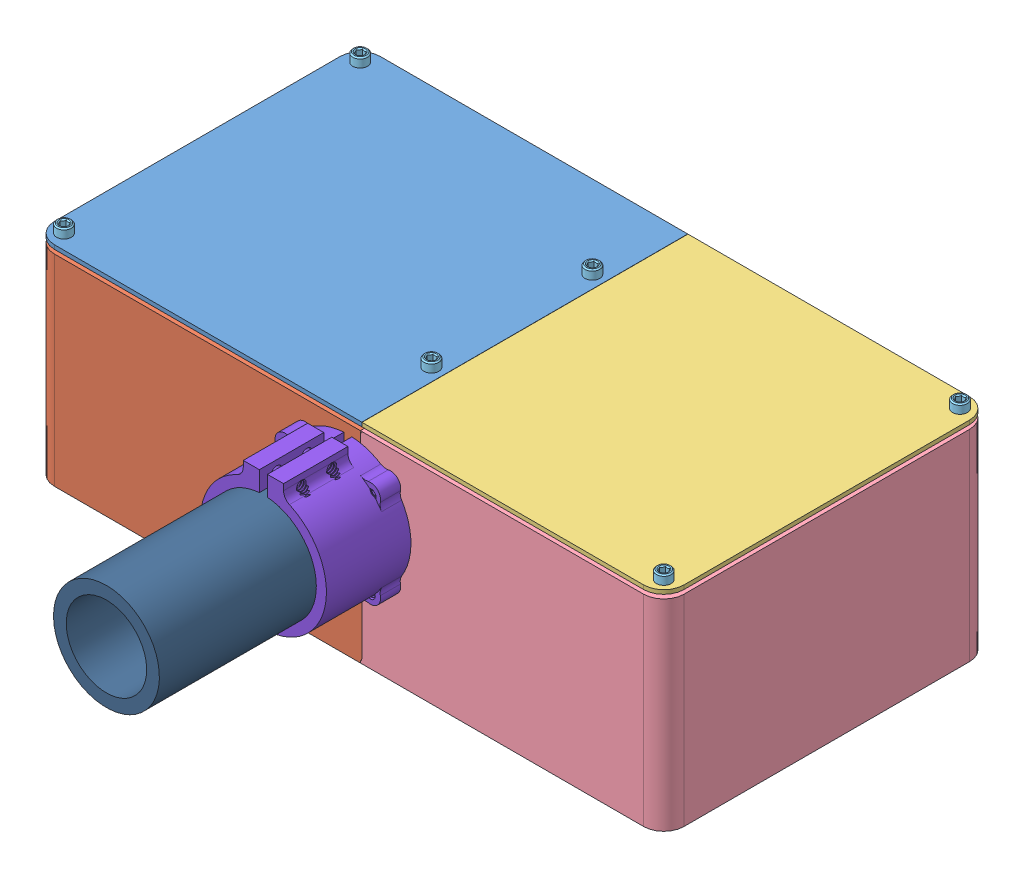
SolidWorks assembly Head Assembly, configuration Default. Lengths in mm.
Overall size (198.69 68.88 181.91).
37 component instances, 13 part files, 51 mates.
Components (placement in the parent):
- Head left back-1: Head left back [Default] at (33.2426 59.719 88.4474) size (103.38 2.54 102.87)
- Head left side-1: Head left side [Left Side] at (83.0901 -3.781 88.4474) size (103.5 63.5 102.87)
- Head right back-1: Head right back [Default] at (132.2391 59.719 88.4474) size (103.5 5.08 102.87)
- Head right side-1: Head right side [Right Side] at (82.3916 -3.781 88.4474) size (103.61 63.5 102.87)
- 4-40_SHCS-1: 4-40_SHCS [4-40 SHCS X .250] at (177.3876 55.909 135.1834) x (1 0 0) z (0 1 0) size (4.65 4.65 9.19)
- 4-40_SHCS-2: 4-40_SHCS [4-40 SHCS X .250] at (82.7091 55.909 113.8474) x (1 0 0) z (0 1 0) size (4.65 4.65 9.19)
- 4-40_SHCS-3: 4-40_SHCS [4-40 SHCS X .250] at (82.7091 55.909 63.0474) x (1 0 0) z (0 1 0) size (4.65 4.65 9.19)
- 4-40_SHCS-4: 4-40_SHCS [4-40 SHCS X .250] at (177.3876 55.909 41.7114) x (1 0 0) z (0 1 0) size (4.65 4.65 9.19)
- 4-40_SHCS-5: 4-40_SHCS [4-40 SHCS X .250] at (-11.9059 55.909 135.1834) x (0.995254 0 0.097312) z (0 1 0) size (4.65 4.65 9.19)
- 4-40_SHCS-6: 4-40_SHCS [4-40 SHCS X .250] at (-11.9059 55.909 41.7114) x (-0.428601 0 -0.903494) z (0 1 0) size (4.65 4.65 9.19)
- 4-40_SHCS-7: 4-40_SHCS [4-40 SHCS X .250] at (82.3916 38.129 43.3624) x (-0.923728 -0.383049 0) z (0 0 -1) size (4.65 4.65 9.19)
- 4-40_SHCS-8: 4-40_SHCS [4-40 SHCS X .250] at (82.3916 17.809 43.3624) x (-0.923728 -0.383049 0) z (0 0 -1) size (4.65 4.65 9.19)
- hex_nut-1: hex_nut [#4-40] at (150.3366 25.429 58.4119) x (-0.837169 0 -0.546944) z (-0.546944 0 0.837169) size (6.35 2.49 8.06)
- hex_nut-2: hex_nut [#4-40] at (116.0466 25.429 58.4119) x (-0.837169 0 -0.546944) z (-0.546944 0 0.837169) size (6.35 2.49 8.06)
- hex_nut-3: hex_nut [#4-40] at (116.0466 25.429 118.4829) x (-0.837169 0 -0.546944) z (-0.546944 0 0.837169) size (6.35 2.49 8.06)
- hex_nut-4: hex_nut [#4-40] at (150.3366 25.429 118.4829) x (-0.837169 0 -0.546944) z (-0.546944 0 0.837169) size (6.35 2.49 8.06)
- 4-40_SHCS-9: 4-40_SHCS [4-40 SHCS X .250] at (150.3366 22.889 58.4119) x (1 0 0) z (0 1 0) size (4.65 4.65 9.19)
- 4-40_SHCS-10: 4-40_SHCS [4-40 SHCS X .250] at (116.0466 22.889 58.4119) x (1 0 0) z (0 1 0) size (4.65 4.65 9.19)
- 4-40_SHCS-11: 4-40_SHCS [4-40 SHCS X .250] at (150.3366 22.889 118.4829) x (1 0 0) z (0 1 0) size (4.65 4.65 9.19)
- 4-40_SHCS-12: 4-40_SHCS [4-40 SHCS X .250] at (116.0466 22.889 118.4829) x (1 0 0) z (0 1 0) size (4.65 4.65 9.19)
- LED Matrix-1: LED Matrix [Default] at (-11.5884 12.729 40.1874) x (1 0 0) z (0 -1 0) size (190.5 96.52 13.21)
- PVC Clamping Hub-1: PVC Clamping Hub [Default] at (82.3916 36.859 166.5524) x (1 0 0) z (0 1 0) size (39.77 26.79 42.81)
- 6-32_SHCS-5: 6-32_SHCS [6-32 SHCS X .250] at (95.862 50.3293 143.0574) x (-0.883865 -0.467742 0) z (0 0 -1) size (5.74 5.74 9.86)
- 6-32_SHCS-6: 6-32_SHCS [6-32 SHCS X .250] at (96.5605 24.0871 143.0574) x (-0.467742 0.883865 0) z (0 0 -1) size (5.74 5.74 9.86)
- 6-32_SHCS-7: 6-32_SHCS [6-32 SHCS X .250] at (70.3182 23.3886 143.0574) x (0.883865 0.467742 0) z (0 0 -1) size (5.74 5.74 9.86)
- 6-32_SHCS-8: 6-32_SHCS [6-32 SHCS X .250] at (69.6197 49.6308 143.0574) x (0.467742 -0.883865 0) z (0 0 -1) size (5.74 5.74 9.86)
- 3in PVC Pipe-1: 3in PVC Pipe [Default] at (82.3916 36.859 139.8824) x (0 0 1) z (-0.871872 0.489734 0) size (76.2 33.4 33.4)
- Logic Shifter Board w components-1: Logic Shifter Board w components [Default] at (139.7225 32.2341 95.9598) x (0 0 1) z (-1 0 0) size (64.77 12.7 39.37)
  - logic shifter board-1: logic shifter board [Default] at (-7.7029 -4.2651 6.531) size (64.77 1.27 39.37)
  - Pin Header 1x4 TH Pitch 2.54mm-1: Pin Header 1x4 TH Pitch 2.54mm [Default] at (-35.2196 -2.9965 -5.3447) x (0 0 1) z (0 1 0) size (10.16 2.54 12.7)
  - Pin Header 1x4 TH Pitch 2.54mm-2: Pin Header 1x4 TH Pitch 2.54mm [Default] at (-35.2196 -2.9965 7.3553) x (0 0 1) z (0 1 0) size (10.16 2.54 12.7)
  - Pin Header 1x4 TH Pitch 2.54mm-3: Pin Header 1x4 TH Pitch 2.54mm [Default] at (-31.4096 -2.9965 7.3553) x (0 0 1) z (0 1 0) size (10.16 2.54 12.7)
  - Pin Header 1x4 TH Pitch 2.54mm-4: Pin Header 1x4 TH Pitch 2.54mm [Default] at (-31.4096 -2.9965 -5.3447) x (0 0 1) z (0 1 0) size (10.16 2.54 12.7)
  - Pin Header 1x4 TH Pitch 2.54mm-5: Pin Header 1x4 TH Pitch 2.54mm [Default] at (19.2941 -2.9965 -5.3447) x (0 0 1) z (0 1 0) size (10.16 2.54 12.7)
  - Pin Header 1x4 TH Pitch 2.54mm-6: Pin Header 1x4 TH Pitch 2.54mm [Default] at (15.4841 -2.9965 -5.3447) x (0 0 1) z (0 1 0) size (10.16 2.54 12.7)
  - Pin Header 1x4 TH Pitch 2.54mm-7: Pin Header 1x4 TH Pitch 2.54mm [Default] at (19.2941 -2.9965 7.3553) x (0 0 1) z (0 1 0) size (10.16 2.54 12.7)
  - Pin Header 1x2 TH Pitch 2.54mm-1: Pin Header 1x2 TH Pitch 2.54mm [Default] at (15.4841 -2.9965 7.3553) x (0 0 1) z (0 1 0) size (5.08 2.54 12.7)
Mates (geometry in assembly coordinates):
- Coincident1: coincident aligned: plane of Head left back-1 through (33.2426 62.259 88.4474) normal (0 1 0); plane of Head right back-1 through (132.2391 62.259 88.4474) normal (0 1 0)
- Concentric1: concentric anti-aligned: cylinder of Head right back-1 through (82.7091 60.989 113.8474) axis (0 1 0) radius 1.1303; cylinder of 4-40_SHCS-2 through (82.7091 74.959 113.8474) axis (0 -1 0) radius 2.3241
- Concentric2: concentric aligned: cylinder of Head right back-1 through (82.7091 60.989 63.0474) axis (0 1 0) radius 1.1303; cylinder of Head left back-1 through (82.7091 62.259 63.0474) axis (0 1 0) radius 1.778
- Concentric3: concentric anti-aligned: cylinder of Head right back-1 through (82.7091 60.989 63.0474) axis (0 1 0) radius 1.1303; cylinder of 4-40_SHCS-3 through (82.7091 74.959 63.0474) axis (0 -1 0) radius 2.3241
- Concentric4: concentric anti-aligned: cylinder of Head left back-1 through (82.7091 62.259 113.8474) axis (0 1 0) radius 1.778; cylinder of 4-40_SHCS-2 through (82.7091 74.959 113.8474) axis (0 -1 0) radius 2.3241
- Concentric5: concentric aligned: cylinder of Head right side-1 through (177.3876 59.719 135.1834) axis (0 1 0) radius 1.1303; cylinder of Head right back-1 through (177.3876 62.259 135.1834) axis (0 1 0) radius 1.7272
- Concentric6: concentric anti-aligned: cylinder of Head right side-1 through (177.3876 59.719 135.1834) axis (0 1 0) radius 1.1303; cylinder of 4-40_SHCS-1 through (177.3876 74.959 135.1834) axis (0 -1 0) radius 2.3241
- Concentric7: concentric aligned: cylinder of Head right side-1 through (177.3876 59.719 41.7114) axis (0 1 0) radius 1.1303; cylinder of Head right back-1 through (177.3876 62.259 41.7114) axis (0 1 0) radius 1.7272
- Concentric8: concentric anti-aligned: cylinder of Head right side-1 through (177.3876 59.719 41.7114) axis (0 1 0) radius 1.1303; cylinder of 4-40_SHCS-4 through (177.3876 74.959 41.7114) axis (0 -1 0) radius 2.3241
- Concentric9: concentric anti-aligned: cylinder of 4-40_SHCS-5 through (-11.9059 74.959 135.1834) axis (0 -1 0) radius 2.3241; cylinder of Head left side-1 through (-11.9059 59.719 135.1834) axis (0 1 0) radius 1.1303
- Concentric10: concentric anti-aligned: cylinder of 4-40_SHCS-5 through (-11.9059 74.959 135.1834) axis (0 -1 0) radius 2.3241; cylinder of Head left back-1 through (-11.9059 62.259 135.1834) axis (0 1 0) radius 1.632
- Concentric11: concentric aligned: cylinder of Head left back-1 through (-11.9059 62.259 41.7114) axis (0 1 0) radius 1.632; cylinder of Head left side-1 through (-11.9059 59.719 41.7114) axis (0 1 0) radius 1.1303
- Concentric12: concentric anti-aligned: cylinder of Head left back-1 through (-11.9059 62.259 41.7114) axis (0 1 0) radius 1.632; cylinder of 4-40_SHCS-6 through (-11.9059 74.959 41.7114) axis (0 -1 0) radius 2.3241
- Coincident2: coincident anti-aligned: plane of Head right back-1 through (132.2391 62.259 88.4474) normal (0 1 0); plane of 4-40_SHCS-1 through (177.3876 62.259 135.1834) normal (0 -1 0)
- Coincident3: coincident anti-aligned: plane of Head right back-1 through (132.2391 62.259 88.4474) normal (0 1 0); plane of 4-40_SHCS-4 through (177.3876 62.259 41.7114) normal (0 -1 0)
- Coincident4: coincident anti-aligned: plane of Head right back-1 through (132.2391 62.259 88.4474) normal (0 1 0); plane of 4-40_SHCS-6 through (-11.9059 62.259 41.7114) normal (0 -1 0)
- Coincident5: coincident anti-aligned: plane of Head right back-1 through (132.2391 62.259 88.4474) normal (0 1 0); plane of 4-40_SHCS-5 through (-11.9059 62.259 135.1834) normal (0 -1 0)
- Coincident6: coincident anti-aligned: plane of Head left back-1 through (33.2426 62.259 88.4474) normal (0 1 0); plane of 4-40_SHCS-2 through (82.7091 62.259 113.8474) normal (0 -1 0)
- Coincident7: coincident anti-aligned: plane of Head left back-1 through (33.2426 62.259 88.4474) normal (0 1 0); plane of 4-40_SHCS-3 through (82.7091 62.259 63.0474) normal (0 -1 0)
- Coincident8: coincident anti-aligned: plane of Head left back-1 through (33.2426 59.719 88.4474) normal (0 -1 0); plane of Head left side-1 through (83.0901 59.719 88.4474) normal (0 1 0)
- Coincident9: coincident anti-aligned: plane of Head left back-1 through (33.2426 59.719 88.4474) normal (0 -1 0); plane of Head right side-1 through (82.3916 59.719 88.4474) normal (0 1 0)
- Concentric13: concentric anti-aligned: cylinder of Head right side-1 through (82.3916 38.129 38.5237) axis (0 0 -1) radius 1.0795; cylinder of 4-40_SHCS-7 through (82.3916 38.129 24.3124) axis (0 0 1) radius 2.3241
- Concentric14: concentric anti-aligned: cylinder of Head right side-1 through (82.3916 17.809 38.5237) axis (0 0 -1) radius 1.0795; cylinder of 4-40_SHCS-8 through (82.3916 17.809 24.3124) axis (0 0 1) radius 2.3241
- Coincident10: coincident anti-aligned: plane of Head right side-1 through (182.0866 0.029 37.0124) normal (0 0 -1); plane of 4-40_SHCS-8 through (82.3916 17.809 37.0124) normal (0 0 1)
- Coincident11: coincident anti-aligned: plane of Head right side-1 through (182.0866 0.029 37.0124) normal (0 0 -1); plane of 4-40_SHCS-7 through (82.3916 38.129 37.0124) normal (0 0 1)
- Concentric18: concentric anti-aligned: cylinder of Head right side-1 through (150.3366 27.969 58.4119) axis (0 1 0) radius 1.632; cylinder of 4-40_SHCS-9 through (150.3366 41.939 58.4119) axis (0 -1 0) radius 2.3241
- Concentric19: concentric anti-aligned: cylinder of Head right side-1 through (150.3366 27.969 58.4119) axis (0 1 0) radius 1.632; cylinder of hex_nut-1 through (150.3366 25.0354 58.4119) axis (0 -1 0) radius 1.0787
- Concentric20: concentric anti-aligned: cylinder of Head right side-1 through (116.0466 27.969 58.4119) axis (0 1 0) radius 1.632; cylinder of 4-40_SHCS-10 through (116.0466 41.939 58.4119) axis (0 -1 0) radius 2.3241
- Concentric21: concentric anti-aligned: cylinder of Head right side-1 through (116.0466 27.969 58.4119) axis (0 1 0) radius 1.632; cylinder of hex_nut-2 through (116.0466 25.0354 58.4119) axis (0 -1 0) radius 1.0787
- Concentric22: concentric anti-aligned: cylinder of Head right side-1 through (150.3366 27.969 118.4829) axis (0 1 0) radius 1.632; cylinder of 4-40_SHCS-11 through (150.3366 41.939 118.4829) axis (0 -1 0) radius 2.3241
- Concentric23: concentric anti-aligned: cylinder of Head right side-1 through (150.3366 27.969 118.4829) axis (0 1 0) radius 1.632; cylinder of hex_nut-4 through (150.3366 25.0354 118.4829) axis (0 -1 0) radius 1.0787
- Concentric24: concentric anti-aligned: cylinder of Head right side-1 through (116.0466 27.969 118.4829) axis (0 1 0) radius 1.632; cylinder of 4-40_SHCS-12 through (116.0466 41.939 118.4829) axis (0 -1 0) radius 2.3241
- Concentric25: concentric anti-aligned: cylinder of Head right side-1 through (116.0466 27.969 118.4829) axis (0 1 0) radius 1.632; cylinder of hex_nut-3 through (116.0466 24.4004 118.4829) axis (0 -1 0) radius 1.0787
- Coincident17: coincident anti-aligned: plane of Head right side-1 through (82.3916 25.429 88.4474) normal (0 -1 0); plane of hex_nut-1 through (152.3418 25.429 55.3427) normal (0 1 0)
- Coincident18: coincident anti-aligned: plane of Head right side-1 through (82.3916 25.429 88.4474) normal (0 -1 0); circle of hex_nut-2
- Coincident19: coincident anti-aligned: plane of Head right side-1 through (82.3916 25.429 88.4474) normal (0 -1 0); plane of hex_nut-4 through (152.3418 25.429 115.4137) normal (0 1 0)
- Coincident20: coincident anti-aligned: plane of Head right side-1 through (82.3916 25.429 88.4474) normal (0 -1 0); plane of hex_nut-3 through (118.0518 25.429 115.4137) normal (0 1 0)
- Coincident21: coincident anti-aligned: plane of Head right side-1 through (178.9116 202.9716 40.1874) normal (0 0 1); plane of LED Matrix-1 through (-11.5884 0.029 40.1874) normal (0 0 -1)
- Coincident22: coincident anti-aligned: plane of Head right side-1 through (178.9116 202.9716 136.7074) normal (-1 0 0); plane of LED Matrix-1 through (178.9116 0.029 40.1874) normal (1 0 0)
- Coincident24: coincident anti-aligned: plane of Head right side-1 through (82.3916 0.029 88.4474) normal (0 1 0); plane of LED Matrix-1 through (-11.5884 0.029 40.1874) normal (0 -1 0)
- Concentric26: concentric anti-aligned: cylinder of Head right side-1 through (82.3916 36.859 141.7874) axis (0 0 -1) radius 9.525; cylinder of PVC Clamping Hub-1 through (82.3916 36.859 139.8824) axis (0 0 1) radius 16.7005
- Concentric29: concentric aligned: cylinder of Head right side-1 through (95.862 50.3293 136.7074) axis (0 0 -1) radius 1.8986; cylinder of PVC Clamping Hub-1 through (95.862 50.3293 139.8824) axis (0 0 -1) radius 1.3526
- Concentric30: concentric anti-aligned: cylinder of Head right side-1 through (95.862 50.3293 136.7074) axis (0 0 -1) radius 1.8986; cylinder of 6-32_SHCS-5 through (95.862 50.3293 124.0074) axis (0 0 1) radius 2.8702
- Coincident25: coincident anti-aligned: plane of Head left side-1 through (-16.6049 0.029 139.8824) normal (0 0 1); plane of PVC Clamping Hub-1 through (82.3916 36.859 139.8824) normal (0 0 -1)
- Coincident26: coincident anti-aligned: plane of Head right side-1 through (82.3916 202.9716 136.7074) normal (0 0 -1); plane of 6-32_SHCS-5 through (95.862 50.3293 136.7074) normal (0 0 1)
- Concentric31: concentric anti-aligned: cylinder of PVC Clamping Hub-1 through (82.3916 36.859 139.8824) axis (0 0 1) radius 16.7005; cylinder of 3in PVC Pipe-1 through (82.3916 36.859 216.0824) axis (0 0 -1) radius 16.7005
- Coincident27: coincident anti-aligned: plane of Head left side-1 through (-16.6049 0.029 139.8824) normal (0 0 1); plane of 3in PVC Pipe-1 through (82.3916 36.859 139.8824) normal (0 0 -1)
- Concentric32: concentric aligned: cylinder of Head right side-1 through (150.3366 27.969 58.4119) axis (0 1 0) radius 1.632; cylinder of Logic Shifter Board w components-1/logic shifter board-1 through (150.3366 29.239 58.4119) axis (0 1 0) radius 1.632
- Concentric33: concentric aligned: cylinder of Head right side-1 through (116.0466 27.969 58.4119) axis (0 1 0) radius 1.632; cylinder of Logic Shifter Board w components-1/logic shifter board-1 through (116.0466 29.239 58.4119) axis (0 1 0) radius 1.632
- Coincident29: coincident anti-aligned: plane of Head right side-1 through (82.3916 27.969 88.4474) normal (0 1 0); plane of Logic Shifter Board w components-1/logic shifter board-1 through (133.1916 27.969 88.2569) normal (0 -1 0)
- Coincident30: coincident anti-aligned: plane of Head right side-1 through (82.3916 0.029 139.8824) normal (0 0 1); plane of PVC Clamping Hub-1 through (82.3916 36.859 139.8824) normal (0 0 -1)
